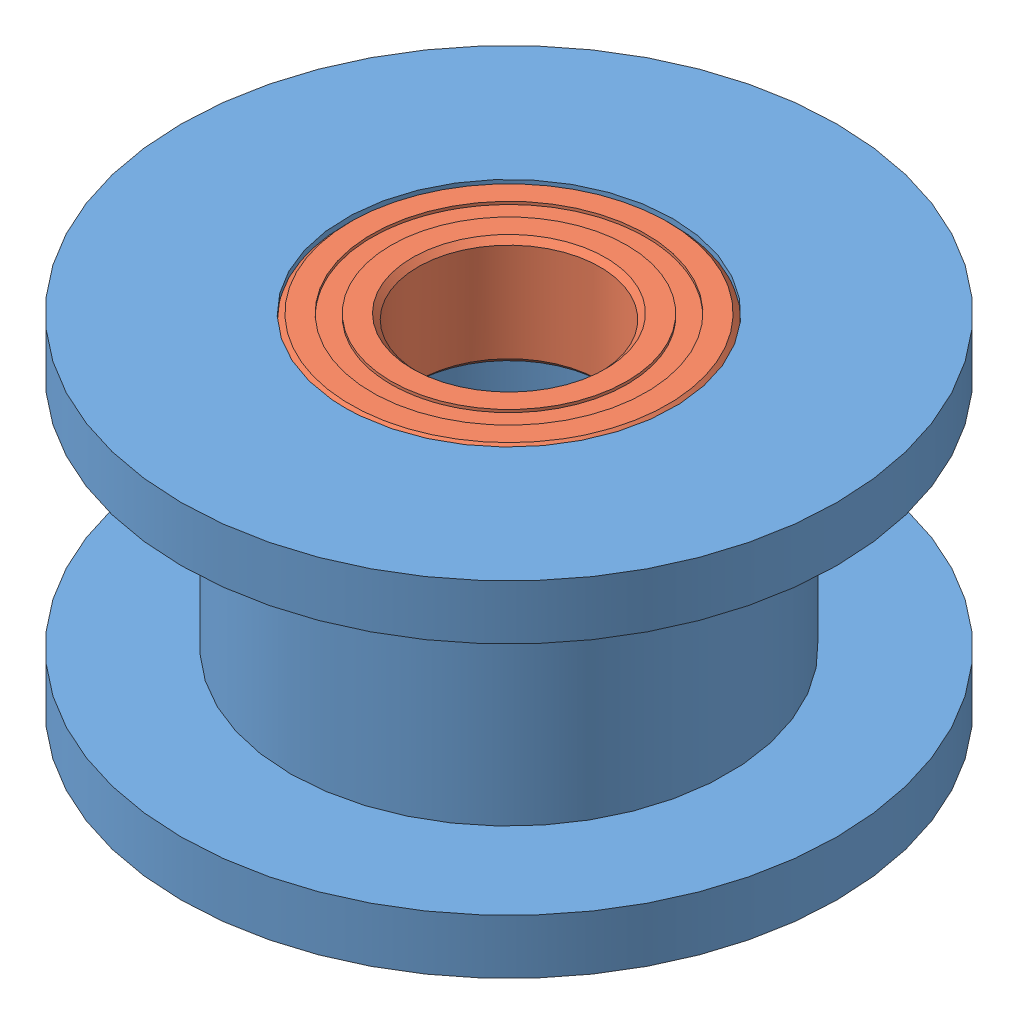
SolidWorks assembly 1037396, configuration Default. Lengths in mm.
Overall size (18 9.45 18).
3 component instances, 2 part files, 3 mates.
Components (placement in the parent):
- 1037396-IDLER PULLEY-1: 1037396-IDLER PULLEY [Default] at origin size (18 9.45 18)
- 1037396-95-2Z BEARING, 9 mm OD, 5 mm ID, 3 mm WIDTH-1: 1037396-95-2Z BEARING, 9 mm OD, 5 mm ID, 3 mm WIDTH [DEFAULT] at (0 3.225 0) x (0.884042 0 0.467408) z (0 1 0) size (9 9 3)
- 1037396-95-2Z BEARING, 9 mm OD, 5 mm ID, 3 mm WIDTH-2: 1037396-95-2Z BEARING, 9 mm OD, 5 mm ID, 3 mm WIDTH [DEFAULT] at (0 -3.225 0) x (-0.884042 0 -0.467408) z (0 -1 0) size (9 9 3)
Mates (geometry in assembly coordinates):
- Coincident1: coordinate: point of 1037396-IDLER PULLEY-1
- Concentric1: concentric anti-aligned: cylinder of 1037396-IDLER PULLEY-1 through (0 3.225 0) axis (0 -1 0) radius 4.5; cylinder of 1037396-95-2Z BEARING, 9 mm OD, 5 mm ID, 3 mm WIDTH-1 through (0 4.725 0) axis (0 1 0) radius 2.5
- Coincident2: coincident aligned: plane of 1037396-IDLER PULLEY-1 through (0 4.725 0) normal (0 1 0); plane of 1037396-95-2Z BEARING, 9 mm OD, 5 mm ID, 3 mm WIDTH-1 through (2.0332 4.725 -3.8456) normal (0 1 0)
